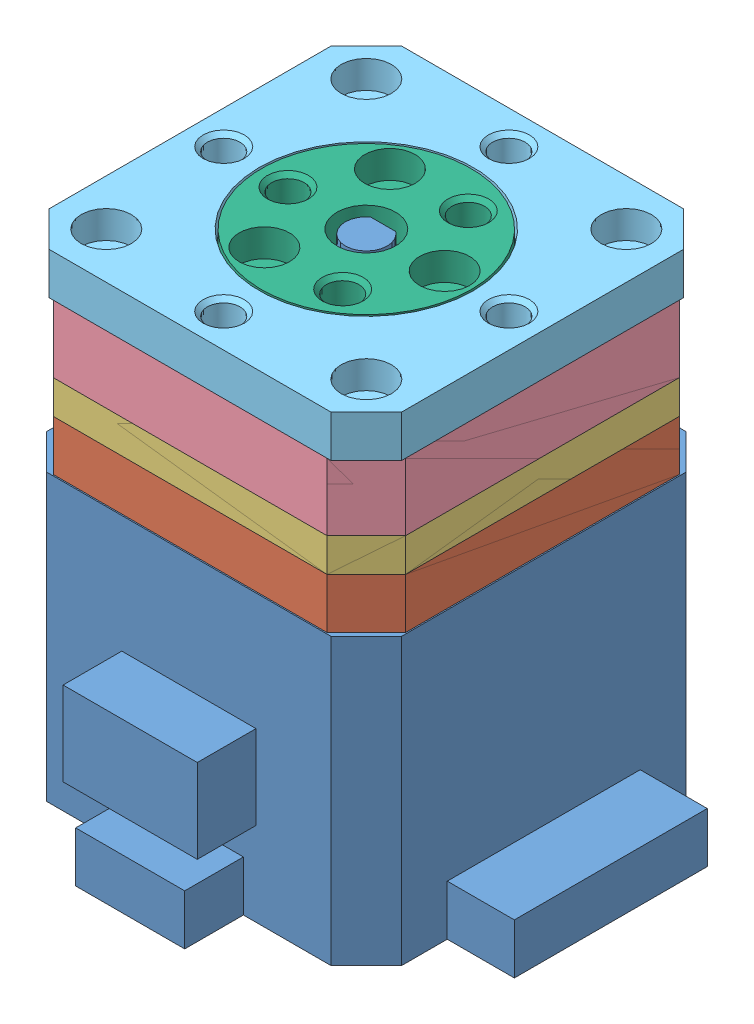
SolidWorks assembly 42步进电机+减速器, configuration 默认. Lengths in mm.
Overall size (50.3 57 49.3).
6 component instances, 6 part files, 17 mates.
Components (placement in the parent):
- 42步进电机-1: 42步进电机 [默认] at origin size (50.3 56.5 49.3)
- 主壳 v1-11-1: 主壳 v1-11 [默认] at (0.15 34 -0.15) x (1 0 0) z (0 1 0) size (42 42 8)
- 主壳 v1-2-1: 主壳 v1-2 [默认] at (0.15 40 -0.15) x (1 0 0) z (0 1 0) size (42 42 4)
- 谐波减速器-1: 谐波减速器 [默认] at (42.15 52 -0.15) x (-1 0 0) z (0 -1 0) size (42 42 10)
- 外壳-上部-1: 外壳-上部 [默认] at (0.15 57 -0.15) x (0 0 -1) z (-1 0 0) size (42 5 42)
- 输出2-1: 输出2 [默认] at (21.15 52 -21.15) x (0.999253 0 -0.03864) z (0.03864 0 0.999253) size (28 5 28)
Mates (geometry in assembly coordinates):
- 重合1: coincident anti-aligned: plane of 42步进电机-1 through (0 34 0) normal (0 1 0); plane of 主壳 v1-11-1 through (3.4 34 -21.15) normal (0 -1 0)
- 距离1: distance = 0.15 mm aligned: plane of 主壳 v1-11-1 through (15.7121 38 -42.15) normal (0 0 -1); plane of 42步进电机-1 through (0 34 -42.3) normal (0 0 -1)
- 距离2: distance = 0.15 mm aligned: plane of 主壳 v1-11-1 through (0.15 36 -15.7121) normal (-1 0 0); plane of 42步进电机-1 through (0 34 0) normal (-1 0 0)
- 重合7: coincident anti-aligned: plane of 主壳 v1-11-1 through (3.4123 40 -2.0454) normal (0 1 0); plane of 主壳 v1-2-1 through (0.8167 40 -15.7121) normal (0 -1 0)
- 重合8: coincident aligned: plane of 主壳 v1-11-1 through (15.7121 38 -42.15) normal (0 0 -1); plane of 主壳 v1-2-1 through (15.7121 42.6667 -42.15) normal (0 0 -1)
- 重合9: coincident aligned: plane of 主壳 v1-11-1 through (0.15 36 -15.7121) normal (-1 0 0); plane of 主壳 v1-2-1 through (0.15 42.6667 -15.7121) normal (-1 0 0)
- 重合10: coincident aligned: plane of 主壳 v1-11-1 through (15.7121 38 -42.15) normal (0 0 -1); plane of 谐波减速器-1 through (26.5879 46.6667 -42.15) normal (0 0 -1)
- 重合11: coincident anti-aligned: plane of 主壳 v1-2-1 through (0.4833 44 -26.4498) normal (0 1 0); plane of 谐波减速器-1 through (41.8167 44 -15.8502) normal (0 -1 0)
- 重合12: coincident aligned: plane of 主壳 v1-11-1 through (0.15 36 -15.7121) normal (-1 0 0); plane of 谐波减速器-1 through (0.15 46.6667 -15.7121) normal (-1 0 0)
- 重合18: coincident aligned: plane of 42步进电机-1 through (0 34 0) normal (0 0 1)
- 重合19: coincident anti-aligned: plane of 42步进电机-1 through (0 0 0) normal (0 -1 0)
- 重合20: coincident anti-aligned: plane of 42步进电机-1 through (0 34 0) normal (-1 0 0)
- 同心8: concentric anti-aligned: cylinder of 42步进电机-1 through (21.15 56.5 -21.15) axis (0 -1 0) radius 2.5; cylinder of 外壳-上部-1 through (21.15 52 -21.15) axis (0 1 0) radius 12.75
- 平行2: parallel aligned: plane of 42步进电机-1 through (42.3 34 0) normal (1 0 0); plane of 外壳-上部-1 through (42.15 52 -0.15) normal (1 0 0)
- 距离3: distance = 18 mm anti-aligned: plane of 42步进电机-1 through (0 34 0) normal (0 1 0); plane of 外壳-上部-1 through (0.15 52 -0.15) normal (0 -1 0)
- 同心9: concentric anti-aligned: cylinder of 42步进电机-1 through (21.15 56.5 -21.15) axis (0 -1 0) radius 2.5; cylinder of 输出2-1 through (21.15 52 -21.15) axis (0 1 0) radius 3.5
- 重合23: coincident aligned: plane of 外壳-上部-1 through (0.15 57 -0.15) normal (0 1 0); plane of 输出2-1 through (21.15 57 -21.15) normal (0 1 0)
